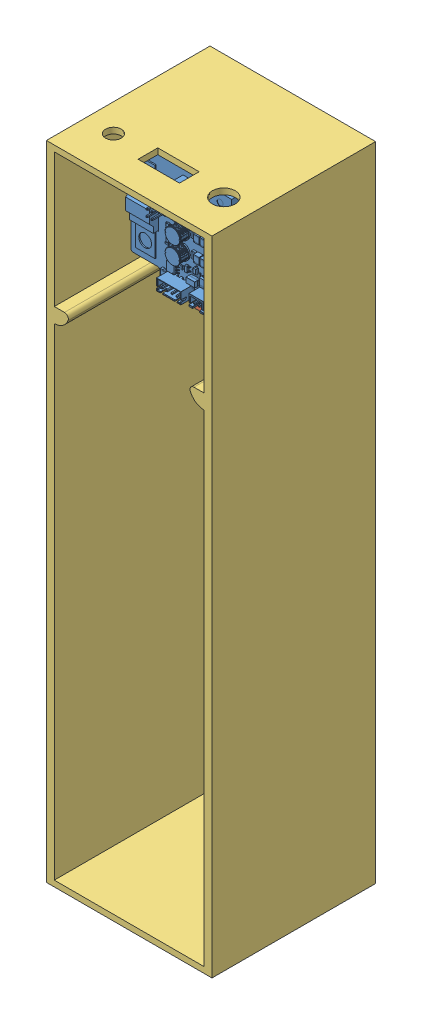
SolidWorks assembly BMS_holder_assembly, configuration Domyślna. Lengths in mm.
Overall size (84 326 83).
4 component instances, 4 part files, 8 mates.
Components (placement in the parent):
- LV_BMS_PCB_V2.step-5: LV_BMS_PCB_V2.step [Domyślna] at (78.395 -4.6801 44.2537) x (-1 0 0) z (0 0 1) size (74.3 66.04 50.52)
- BMS_holder-1: BMS_holder [Domyślna] at (0.6 -0.1 -59.5553) x (-1 0 0) z (0 0 -1) size (75.7 69.67 43.75)
- bomba_container_v6_maxi-1: bomba_container_v6_maxi [Domyślna] at (42 -163 0) size (84 326 83)
- BMS_HOLDER_screw_connector_for_pcb-1: BMS_HOLDER_screw_connector_for_pcb [Domyślna] at (0.6 -0.1 5.5) size (75.7 9.29 40)
Mates (geometry in assembly coordinates):
- Coincident7: coincident anti-aligned: plane of bomba_container_v6_maxi-1 through (0 0 0) normal (-1 0 0)
- Coincident8: coincident anti-aligned: plane of bomba_container_v6_maxi-1 through (42 -163 0) normal (0 0 -1)
- Coincident9: coincident aligned: plane of bomba_container_v6_maxi-1 through (84 0 0) normal (0 1 0)
- Distance3: distance = 0.1 mm anti-aligned: plane of bomba_container_v6_maxi-1 through (80 -70.9701 3.75) normal (-1 0 0); plane of BMS_holder-1 through (79.9 -0.1 5.5) normal (1 0 0)
- Distance4: distance = 0.1 mm anti-aligned: plane of BMS_holder-1 through (0.6 -70.8701 5.5) normal (0 -1 0); plane of bomba_container_v6_maxi-1 through (74.8387 -70.9701 3.75) normal (0 1 0)
- Coincident12: coincident anti-aligned: plane of BMS_holder-1 through (80 -71.0173 2.5) normal (0 0 -1); plane of bomba_container_v6_maxi-1 through (80 -71.0173 2.5) normal (0 0 1)
- Concentric1: concentric anti-aligned: cylinder of BMS_holder-1 through (9.2 -6.65 2.5) axis (0 0 1) radius 1.7; cylinder of BMS_HOLDER_screw_connector_for_pcb-1 through (9.2 -6.65 9) axis (0 0 -1) radius 1.6
- Coincident13: coincident anti-aligned: plane of BMS_holder-1 through (0.6 -0.1 5.5) normal (0 0 1); plane of BMS_HOLDER_screw_connector_for_pcb-1 through (0.6 -10.15 5.5) normal (0 0 -1)
